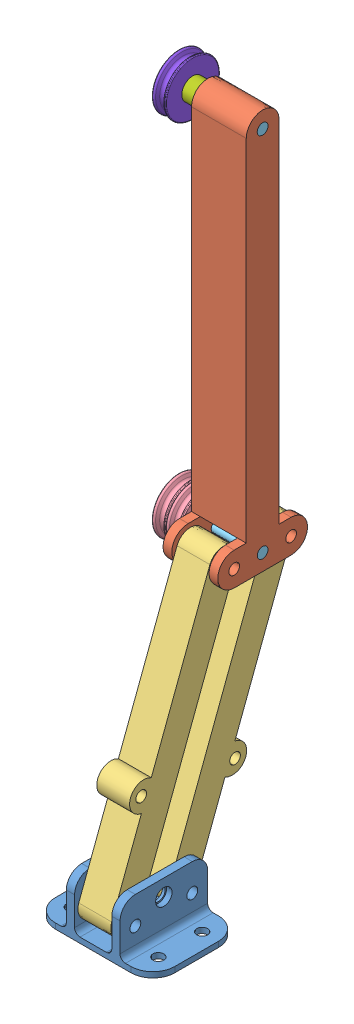
SolidWorks assembly Arm Assem, configuration Default. Lengths in mm.
Overall size (75.88 397.22 129.71).
10 component instances, 8 part files, 20 mates.
Components (placement in the parent):
- Mounting Bracket-1: Mounting Bracket [Default] at origin size (69.22 31.75 50.8)
- Contact Arm-1: Contact Arm [Default] at (-15.875 166.7605 -48.1016) x (0 1 0) z (1 0 0) size (231.78 52.07 31.75)
- Parallel Arm-2: Parallel Arm [Default] at (9.525 91.3177 13.4142) x (0 0.935492 -0.353348) z (0 0.353348 0.935492) size (177.8 19.05 26.35)
- Parallel Arm-5: Parallel Arm [Default] at (-9.525 91.3177 -19.6058) x (0 0.935492 -0.353348) z (0 -0.353348 -0.935492) size (177.8 19.05 26.35)
- Elbow Pulley-1: Elbow Pulley [Default] at (-28.6687 166.7605 -31.5916) x (0 -0.025414 -0.999677) z (1 0 0) size (31.4 31.4 16)
- Elbow Pulley Shaft-1: Elbow Pulley Shaft [Default] at (15.875 166.7605 -31.5916) x (0 0 1) z (-1 0 0) size (6.35 6.35 57.15)
- Elbow Pulley Washer-1: Elbow Pulley Washer [Default] at (-16.6687 166.7605 -31.5916) x (0 -0.99991 0.013398) z (0 0.013398 0.99991) size (12.7 0.79 12.7)
- End Pulley Spacer-1: End Pulley Spacer [Default] at (-24.6687 379.4855 -31.5916) x (0 0 -1) z (1 0 0) size (12.7 12.7 8.79)
- Base Pulley-1: Base Pulley [Default] at (-28.6687 379.4855 -31.5916) x (0 0.139265 0.990255) z (-1 0 0) size (31.4 31.4 8)
- Elbow Pulley Shaft-2: Elbow Pulley Shaft [Default] at (15.875 379.4855 -31.5916) x (0 0 1) z (-1 0 0) size (6.35 6.35 57.15)
Mates (geometry in assembly coordinates):
- Concentric2: concentric: cylinder of Mounting Bracket-1 through (34.6075 15.875 41.91) axis (-1 0 0) radius 3.175; cylinder of Parallel Arm-2 through (-9.525 15.875 41.91) axis (1 0 0) radius 3.1115
- Concentric5: concentric: cylinder of Contact Arm-1 through (17.145 166.7605 -15.0816) axis (-1 0 0) radius 3.1115; cylinder of Parallel Arm-2 through (-9.525 166.7605 -15.0816) axis (1 0 0) radius 3.1115
- Parallel1: parallel: plane of Parallel Arm-2 through (-9.525 12.9581 34.1875) normal (0 -0.353348 -0.935492); plane of Parallel Arm-5 through (9.525 18.7919 16.6125) normal (0 0.353348 0.935492)
- Concentric8: concentric: cylinder of Mounting Bracket-1 through (34.6075 15.875 8.89) axis (-1 0 0) radius 3.175; cylinder of Parallel Arm-5 through (9.525 15.875 8.89) axis (-1 0 0) radius 3.1115
- Width2: width: plane of Contact Arm-1 through (10.795 176.2855 -48.1016) normal (-1 0 0); plane of Contact Arm-1 through (-10.795 176.2855 -48.1016) normal (1 0 0); plane of Parallel Arm-5 through (-9.525 15.875 8.89) normal (-1 0 0); plane of Parallel Arm-5 through (9.525 15.875 8.89) normal (1 0 0)
- Concentric9: concentric: cylinder of Contact Arm-1 through (17.145 166.7605 -48.1016) axis (-1 0 0) radius 3.1115; cylinder of Parallel Arm-5 through (9.525 166.7605 -48.1016) axis (-1 0 0) radius 3.1115
- Concentric10: concentric: cylinder of Contact Arm-1 through (17.145 166.7605 -31.5916) axis (-1 0 0) radius 3.1115; cylinder of Elbow Pulley Shaft-1 through (-40.005 166.7605 -31.5916) axis (1 0 0) radius 3.175
- Coincident8: coincident: plane of Contact Arm-1 through (17.145 166.7605 -48.1016) normal (1 0 0); plane of Elbow Pulley Shaft-1 through (17.145 166.7605 -31.5916) normal (1 0 0)
- Concentric11: concentric: cylinder of Elbow Pulley-1 through (-21.3987 166.7605 -31.5916) axis (-1 0 0) radius 6.35; cylinder of Elbow Pulley Shaft-1 through (-40.005 166.7605 -31.5916) axis (1 0 0) radius 3.175
- Concentric12: concentric: cylinder of Elbow Pulley Shaft-1 through (-40.005 166.7605 -31.5916) axis (1 0 0) radius 3.175; cylinder of Elbow Pulley Washer-1 through (-14.605 166.7605 -31.5916) axis (-1 0 0) radius 3.175
- Coincident9: coincident: plane of Contact Arm-1 through (-14.605 166.7605 -48.1016) normal (-1 0 0); plane of Elbow Pulley Washer-1 through (-14.605 166.7605 -31.5916) normal (1 0 0)
- Coincident10: coincident: plane of Elbow Pulley-1 through (-15.3987 166.7605 -31.5916) normal (1 0 0); plane of Elbow Pulley Washer-1 through (-15.3987 166.7605 -31.5916) normal (-1 0 0)
- Coincident16: coincident: plane of Contact Arm-1 through (-14.605 166.7605 -48.1016) normal (-1 0 0); plane of End Pulley Spacer-1 through (-14.605 379.4855 -31.5916) normal (1 0 0)
- Coincident17: coincident: plane of End Pulley Spacer-1 through (-23.3987 379.4855 -31.5916) normal (-1 0 0); plane of Base Pulley-1 through (-23.3987 379.4855 -31.5916) normal (1 0 0)
- Concentric20: concentric: cylinder of Contact Arm-1 through (17.145 379.4855 -31.5916) axis (-1 0 0) radius 3.1115; cylinder of Elbow Pulley Shaft-2 through (-40.005 379.4855 -31.5916) axis (1 0 0) radius 3.175
- Coincident18: coincident: plane of Contact Arm-1 through (17.145 166.7605 -48.1016) normal (1 0 0); plane of Elbow Pulley Shaft-2 through (17.145 379.4855 -31.5916) normal (1 0 0)
- Concentric22: concentric: cylinder of End Pulley Spacer-1 through (-14.605 379.4855 -31.5916) axis (-1 0 0) radius 3.175; cylinder of Elbow Pulley Shaft-2 through (-40.005 379.4855 -31.5916) axis (1 0 0) radius 3.175
- Concentric23: concentric: cylinder of Base Pulley-1 through (-23.3987 379.4855 -31.5916) axis (-1 0 0) radius 4.7625; cylinder of Elbow Pulley Shaft-2 through (-40.005 379.4855 -31.5916) axis (1 0 0) radius 3.175
- Coincident19: coincident: plane of Parallel Arm-2 through (-9.525 15.875 41.91) normal (-1 0 0); plane of Parallel Arm-5 through (-9.525 15.875 8.89) normal (-1 0 0)
- Width1: width: plane of Parallel Arm-2 through (-9.525 15.875 41.91) normal (-1 0 0); plane of Parallel Arm-2 through (9.525 15.875 41.91) normal (1 0 0); plane of Mounting Bracket-1 through (-10.795 3.175 50.8) normal (1 0 0); plane of Mounting Bracket-1 through (10.795 31.75 50.8) normal (-1 0 0)
